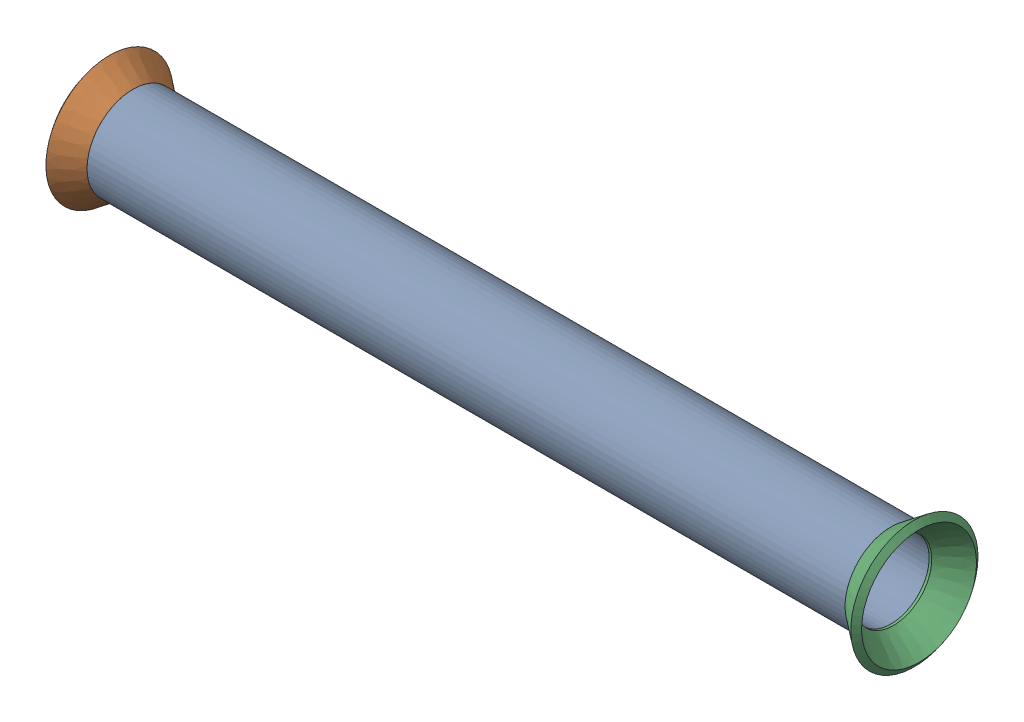
SolidWorks assembly Pipe 52, configuration Default. Lengths in mm.
Overall size (112.62 22.99 22.99).
3 component instances, 2 part files, 2 mates.
Components (placement in the parent):
- Copy of Part2-1: Copy of Part2 [Default<As Machined>] at (-870.9999 -1071.2689 485.9354) x (-1 0 0) z (0 0 -1) size (104.85 12.7 12.7)
- Flared pipe end - .5 inch-1: Flared pipe end - .5 inch [Default<As Machined>] at (-832.2315 400.5908 485.9354) x (0 0.383049 -0.923728) z (-1 0 0) size (17.59 17.59 3.89)
- Flared pipe end - .5 inch-3: Flared pipe end - .5 inch [Default<As Machined>] at (-727.386 400.5908 485.9354) x (0 -0.383049 0.923728) z (1 0 0) size (17.59 17.59 3.89)
Mates (geometry in assembly coordinates):
- Coincident1567: coincident: circle of Copy of Part2-1; circle of Flared pipe end - .5 inch-1
- Coincident1653: coincident: circle of Copy of Part2-1; circle of Flared pipe end - .5 inch-3
